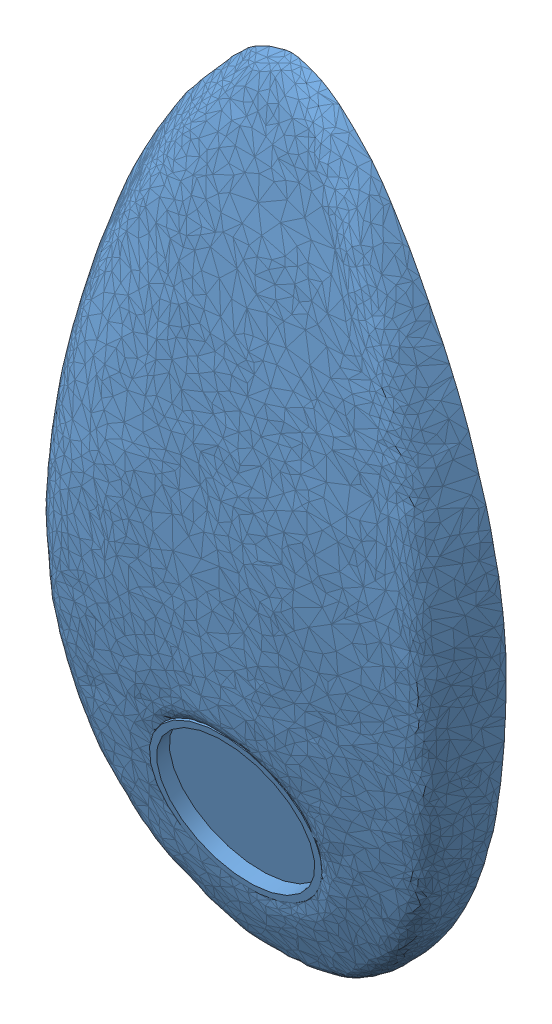
SolidWorks assembly Assem14, configuration Default. Lengths in mm.
Overall size (73.66 119.76 19.55).
2 component instances, 2 part files, 4 mates.
Components (placement in the parent):
- part_housingPrepared-1: part_housingPrepared [Default] at (1.4093 9.2175 -30.0595) size (64.09 119.76 15.04)
- housing-1: housing [Default] at (4.9153 -42.8288 -7.0764) x (0.410927 0.911623 0.009121) z (-0.904021 0.406167 0.133324) size (60.5 8.65 49)
Mates (geometry in assembly coordinates):
- Parallel3: parallel aligned: plane of part_housingPrepared-1 through (-1.6236 -37.4871 -0.1824) normal (0.037263 -0.23582 0.971082); plane of housing-1 through (5.0708 -43.8132 -3.023) normal (0.037263 -0.23582 0.971082)
- Coincident6: coincident: plane of part_housingPrepared-1 through (-1.6236 -37.4871 -0.1824) normal (0.037263 -0.23582 0.971082); line of housing-1 through (-10.2195 -43.3359 -1.2729) axis (0.904021 -0.406167 -0.133324)
- Coincident7: coincident: line of part_housingPrepared-1 through (-1.4909 -38.3264 3.2736) axis (-0.037263 0.23582 -0.971082); point of housing-1
- Parallel4: parallel anti-aligned: line of part_housingPrepared-1 through (7.524 -35.4721 3.6208) axis (-0.904021 0.406167 0.133324); line of housing-1 through (-10.2195 -43.3359 -1.2729) axis (0.904021 -0.406167 -0.133324)
